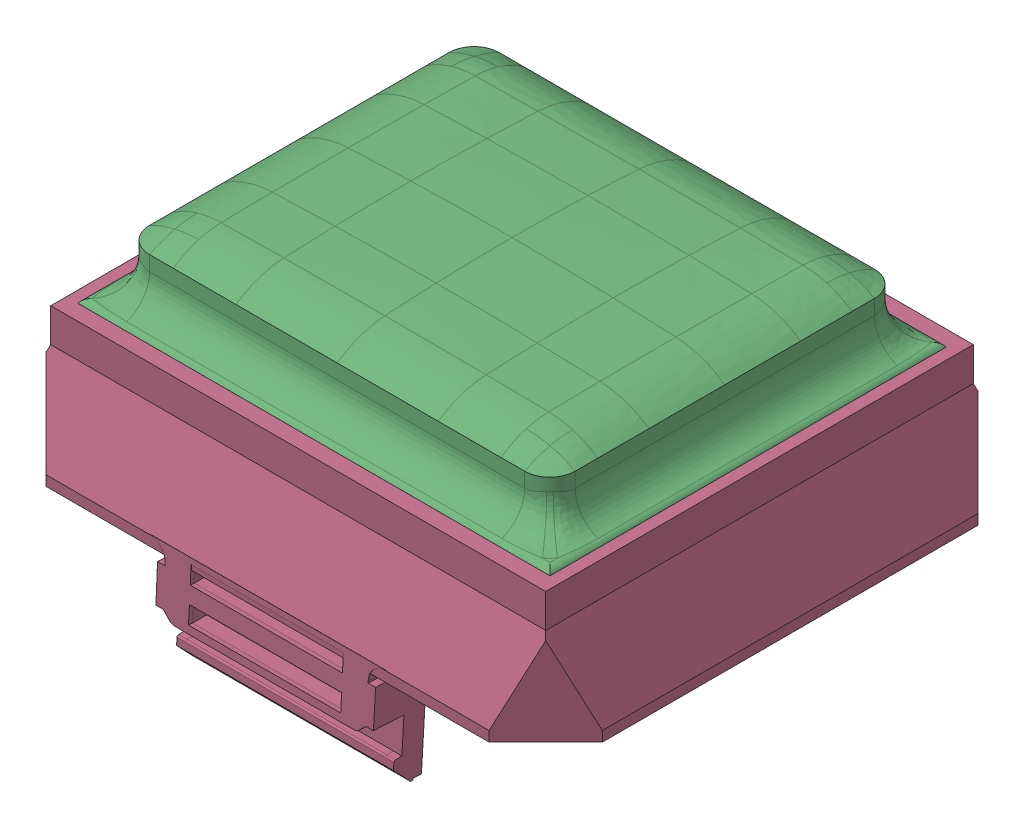
SolidWorks assembly PinDesign_2mm, configuration 默认. Lengths in mm.
Overall size (33 17.51 29.5).
6 component instances, 6 part files, 16 mates.
Components (placement in the parent):
- Lens-1: Lens [默认] at origin size (28.33 2.18 23.83)
- InsideSkin_2mm-1: InsideSkin_2mm [默认] at (0.0001 0 0.2499) size (23.8 5.49 19.29)
- Topskin-1: Topskin [默认] at (0.0001 2 0.2499) size (28.02 6.25 23.52) (hidden)
- Supportbase-2: Supportbase [默认] at origin size (33 14.02 29.5)
- Pinmarker2mm_1-1: Pinmarker2mm_1 [默认] at (0.0001 0 0.2499) size (21.57 1.99 16.56)
- markerTopTip-1: markerTopTip [默认] at (-10.0749 22.5 -7.8251) x (1 0 0) z (0 -1 0) size (21.2 16.2 0.4)
Mates (geometry in assembly coordinates):
- 同心2: concentric anti-aligned: cylinder of InsideSkin-1 through (10.8751 17.7531 8.6249) axis (0 1 0) radius 0.7; cylinder of Board3Con1612611OriginalSkin_TOP-1 through (10.8751 24 8.6249) axis (0 -1 0) radius 0.7
- 同心3: concentric anti-aligned: cylinder of InsideSkin-1 through (10.8751 17.7531 -9.1251) axis (0 1 0) radius 0.7; cylinder of Board3Con1612611OriginalSkin_TOP-1 through (10.8751 24 -9.1251) axis (0 -1 0) radius 0.7
- 重合4: coincident aligned: plane of InsideSkin-1 through (10.8751 19 -9.1251) normal (0 -1 0); plane of Board3Con1612611OriginalSkin_TOP-1 through (0.0001 19 0.2499) normal (0 -1 0)
- 重合6: coordinate: point of NewContiSupportBase-2
- 重合7: coincident anti-aligned: plane of lensall-1 through (13.75 19 -11.5) normal (0.939693 0.34202 0); plane of NewContiSupportBase-2 through (13.75 19 12.7803) normal (-0.939693 -0.34202 0)
- 同心5: concentric aligned: cylinder of lensall-1 through (13.3294 18.6938 -11.0794) axis (-0.323616 0.889126 0.323616) radius 0.5; cylinder of NewContiSupportBase-2 through (10.7866 25.6801 -8.5366) axis (-0.323616 0.889126 0.323616) radius 0.5
- 重合8: coincident anti-aligned: plane of lensall-1 through (0 18 0) normal (0 -1 0); plane of NewContiSupportBase-2 through (0 18 0) normal (0 1 0)
- 重合9: coincident anti-aligned: plane of lensall-1 through (0 19 0) normal (0 1 0); plane of Board3Con1612611OriginalSkin_TOP-1 through (0.0001 19 0.2499) normal (0 -1 0)
- 重合10: coincident anti-aligned: plane of Board3Con1612611OriginalSkin_TOP-1 through (0.0001 19 11.7499) normal (0 0 1); plane of NewContiSupportBase-2 through (-13.5999 21 11.7499) normal (0 0 -1)
- 重合11: coincident anti-aligned: plane of Board3Con1612611OriginalSkin_TOP-1 through (14.0001 19 0.2499) normal (1 0 0); plane of NewContiSupportBase-2 through (14.0001 21 11.7499) normal (-1 0 0)
- 重合12: coincident anti-aligned: plane of InsideSkin-1 through (-10.0749 22.1 7.1749) normal (0 1 0); plane of markerTopTip-1 through (-10.0749 22.1 7.1749) normal (0 -1 0)
- 同心6: concentric aligned: cylinder of markerTopTip-1 through (-10.0749 22.1 7.1749) axis (0 1 0) radius 0.6; circle of Pinmarker1mm_1-1
- 重合13: coincident anti-aligned: plane of Pinmarker1mm_1-1 through (-10.0749 22.5 7.1749) normal (0 -1 0); plane of markerTopTip-1 through (-10.0749 22.5 7.1749) normal (0 1 0)
- 同心7: concentric aligned: cone of InsideSkin-1 through (-10.0749 22.5 7.1749) axis (0 -1 0); cone of Pinmarker1mm_1-1 through (-10.0749 22.5 7.1749) axis (0 -1 0)
- 同心8: concentric aligned: cone of InsideSkin-1 through (-10.0749 22.5 -7.8251) axis (0 -1 0); cone of Pinmarker1mm_1-1 through (-10.0749 22.5 -7.8251) axis (0 -1 0)
- 同心9: concentric anti-aligned: cone of Pinmarker1mm_1-1 through (-10.0749 22.5 4.6749) axis (0 -1 0); cylinder of markerTopTip-1 through (-10.0749 22.1 4.6749) axis (0 1 0) radius 0.6
